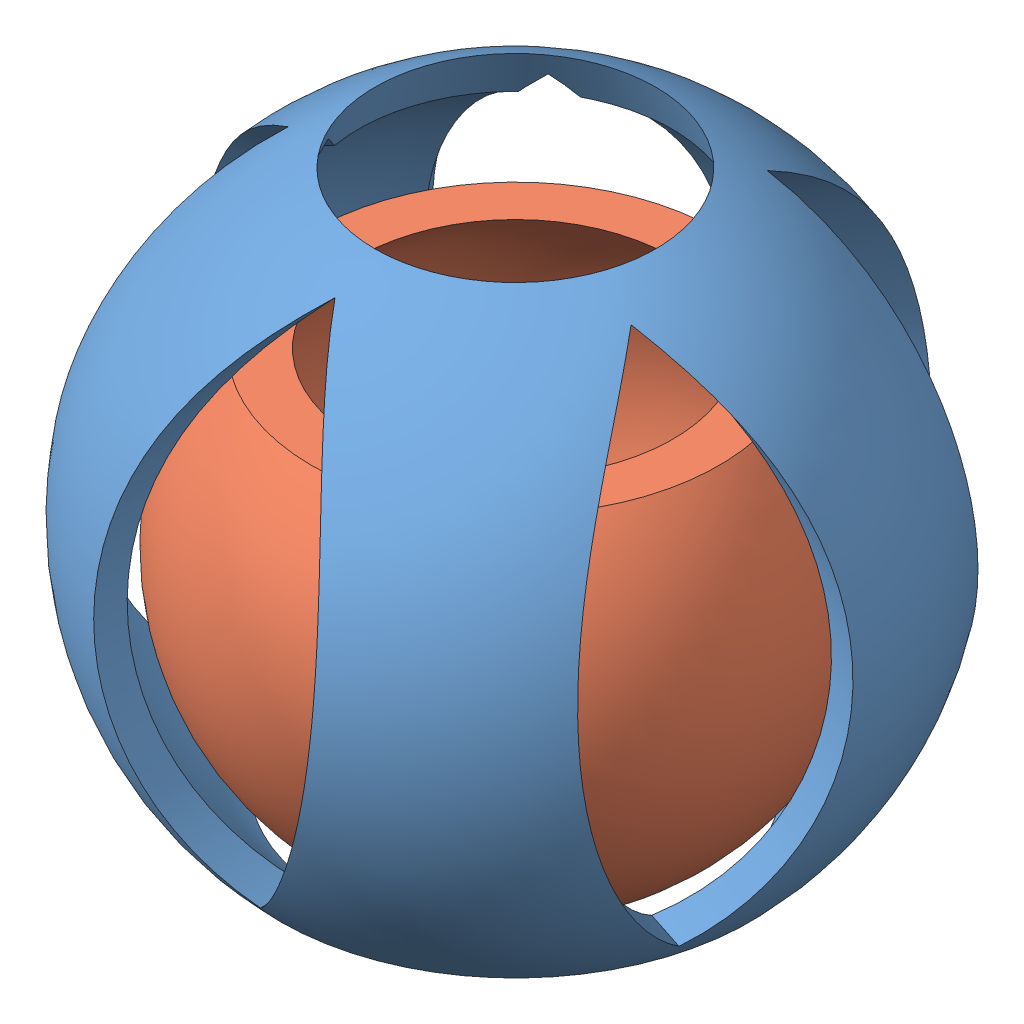
SolidWorks assembly pieces, configuration Default. Lengths in mm.
Overall size (32.09 25.64 32.09).
2 component instances, 2 part files, 1 mates.
Components (placement in the parent):
- outer_ball-1: outer_ball [Default] at origin size (30 24.2 30)
- inner_ball-2: inner_ball [Default] at (0 -1.1708 0) x (-0.898878 0 -0.4382) z (-0.4382 0 0.898878) size (24 18.59 24)
Mates (geometry in assembly coordinates):
- Concentric2: concentric anti-aligned: circle of outer_ball-1; circle of inner_ball-2
